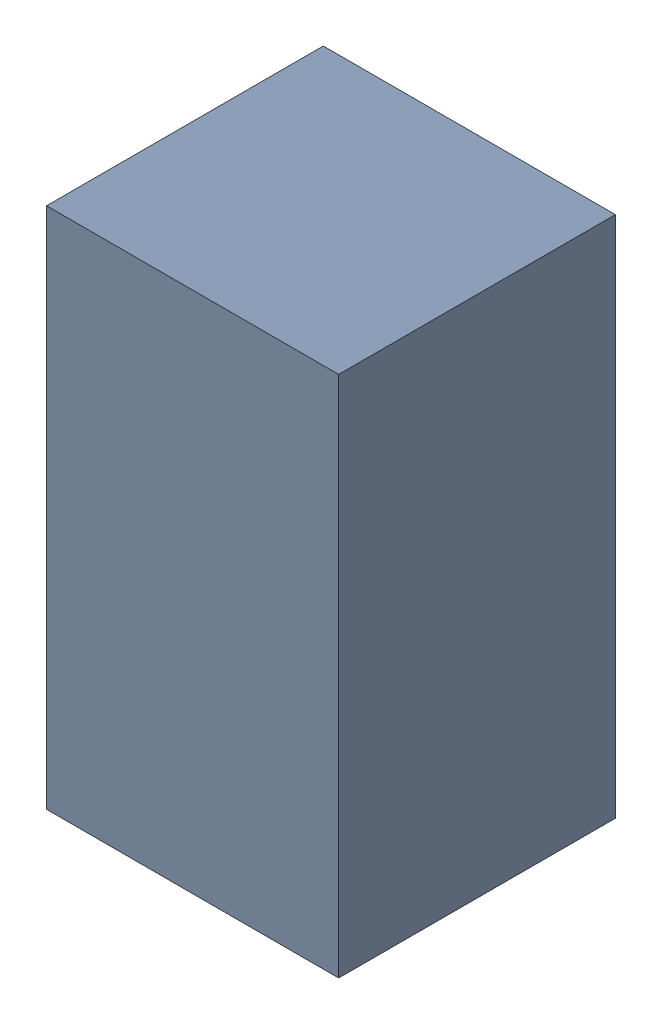
SolidWorks assembly R206, configuration Standard. Lengths in mm.
Overall size (0.95 1.7 0.9).
2 component instances, 1 part files, 0 mates.
Components (placement in the parent):
- 885541560-1: 885541560 [Standard] at (4.85 -13 0) size (0.95 1.7 0.9)
  - Extruded_16-1: Extruded_16 [Standard] at origin size (0.95 1.7 0.9)
